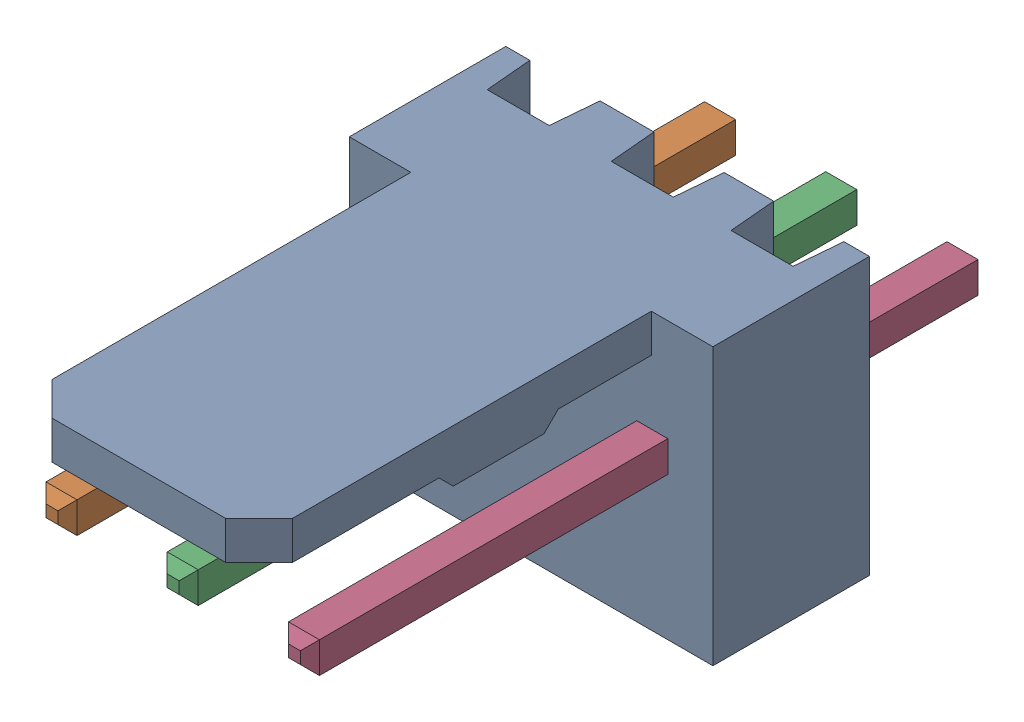
SolidWorks assembly Molex PCB 3 pin v2 v6_1, configuration Predeterminado. Lengths in mm.
Overall size (7.62 5.79 14.92).
4 component instances, 2 part files, 0 mates.
Components (placement in the parent):
- BASE9710016_2-1: BASE9710016_2 [Predeterminado] at (2.54 2.895 -8.22) size (7.62 5.79 11.5)
- PINO9710016_2-1: PINO9710016_2 [Predeterminado] at (1.27 3.325 -0.72) size (0.65 0.65 14.2)
- PINO9710016_2-2: PINO9710016_2 [Predeterminado] at (3.81 3.325 -0.72) size (0.65 0.65 14.2)
- PINO9710016_2-3: PINO9710016_2 [Predeterminado] at (6.35 3.325 -0.72) size (0.65 0.65 14.2)
